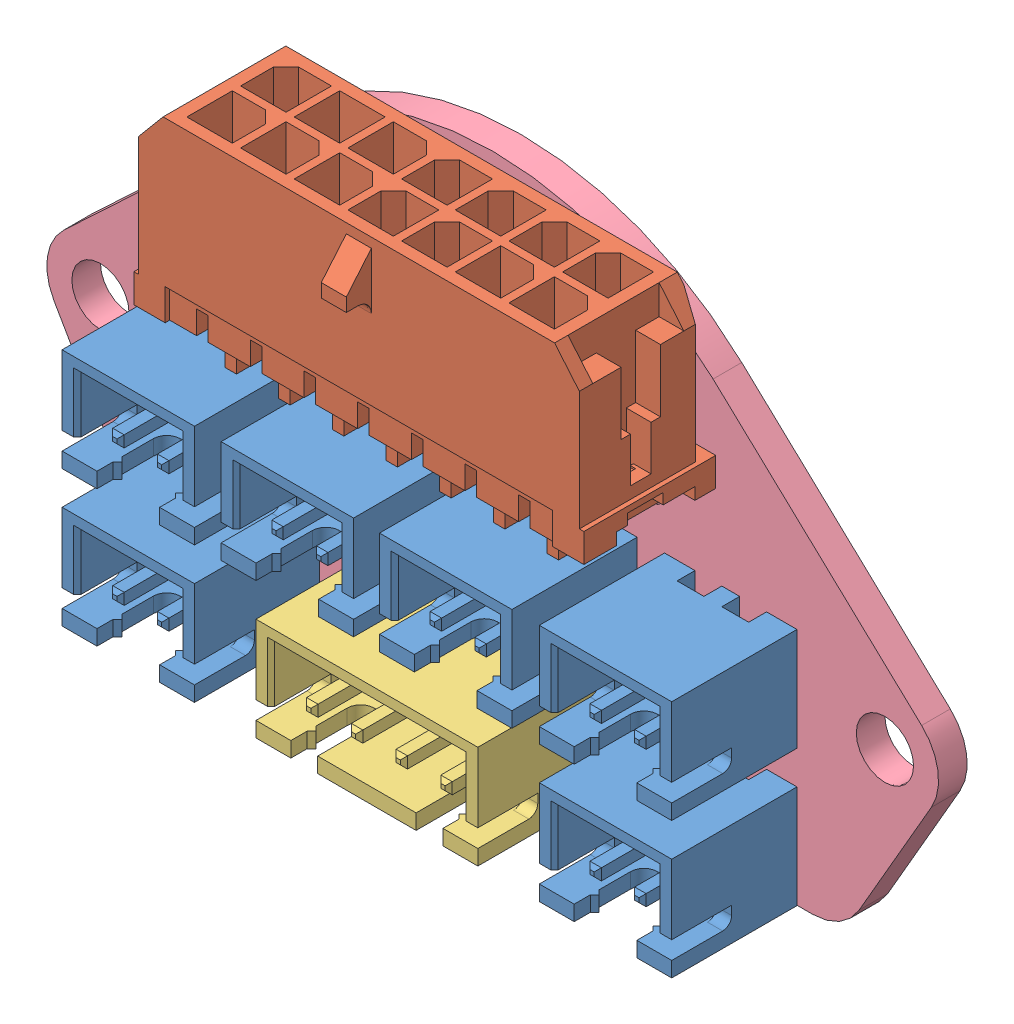
SolidWorks assembly Toolhead_PCB, configuration Default. Lengths in mm.
Overall size (49.84 28 12.23).
18 component instances, 4 part files, 0 mates.
Components (placement in the parent):
- Toolhead_PCB.step-1: Toolhead_PCB.step [Default] at origin size (49.84 28 12.23)
  - JST_XH_B2B-XH-A_1x02_P2.50mm_Vertical.step-1: JST_XH_B2B-XH-A_1x02_P2.50mm_Vertical.step [Default] at (-12.065 -4 1.65) x (-1 0 0) z (0 0 1) size (7.4 5.75 10.4)
    - SOLID.step-1: SOLID.step [Default] at origin size (7.4 5.75 10.4)
  - JST_XH_B2B-XH-A_1x02_P2.50mm_Vertical.step-2: JST_XH_B2B-XH-A_1x02_P2.50mm_Vertical.step [Default] at (5.675 -4 1.65) x (-1 0 0) z (0 0 1) size (7.4 5.75 10.4)
    - SOLID.step-1: SOLID.step [Default] at origin size (7.4 5.75 10.4)
  - JST_XH_B2B-XH-A_1x02_P2.50mm_Vertical.step-3: JST_XH_B2B-XH-A_1x02_P2.50mm_Vertical.step [Default] at (-12.065 -11.62 1.65) x (-1 0 0) z (0 0 1) size (7.4 5.75 10.4)
    - SOLID.step-1: SOLID.step [Default] at origin size (7.4 5.75 10.4)
  - 430451400.step-1: 430451400.step [Default] at (0 8.97 5.65) x (-1 0 0) z (0 1 0) size (25.15 11.95 12.24)
    - SOLID-0.step-1: SOLID-0.step [Default] at origin size (25.15 11.95 12.24)
  - JST_XH_B2B-XH-A_1x02_P2.50mm_Vertical.step-4: JST_XH_B2B-XH-A_1x02_P2.50mm_Vertical.step [Default] at (14.605 -11.62 1.65) x (-1 0 0) z (0 0 1) size (7.4 5.75 10.4)
    - SOLID.step-1: SOLID.step [Default] at origin size (7.4 5.75 10.4)
  - JST_XH_B2B-XH-A_1x02_P2.50mm_Vertical.step-5: JST_XH_B2B-XH-A_1x02_P2.50mm_Vertical.step [Default] at (-3.175 -4 1.65) x (-1 0 0) z (0 0 1) size (7.4 5.75 10.4)
    - SOLID.step-1: SOLID.step [Default] at origin size (7.4 5.75 10.4)
  - JST_XH_B2B-XH-A_1x02_P2.50mm_Vertical.step-6: JST_XH_B2B-XH-A_1x02_P2.50mm_Vertical.step [Default] at (14.605 -4 1.65) x (-1 0 0) z (0 0 1) size (7.4 5.75 10.4)
    - SOLID.step-1: SOLID.step [Default] at origin size (7.4 5.75 10.4)
  - JST_XH_B4B-XH-A_1x04_P2.50mm_Vertical.step-1: JST_XH_B4B-XH-A_1x04_P2.50mm_Vertical.step [Default] at (3.77 -11.62 1.65) x (-1 0 0) z (0 0 1) size (12.4 5.75 10.4)
    - SOLID-1.step-1: SOLID-1.step [Default] at origin size (12.4 5.75 10.4)
  - COMPOUND.step-1: COMPOUND.step [Default] at origin size (49.84 28 1.6)
